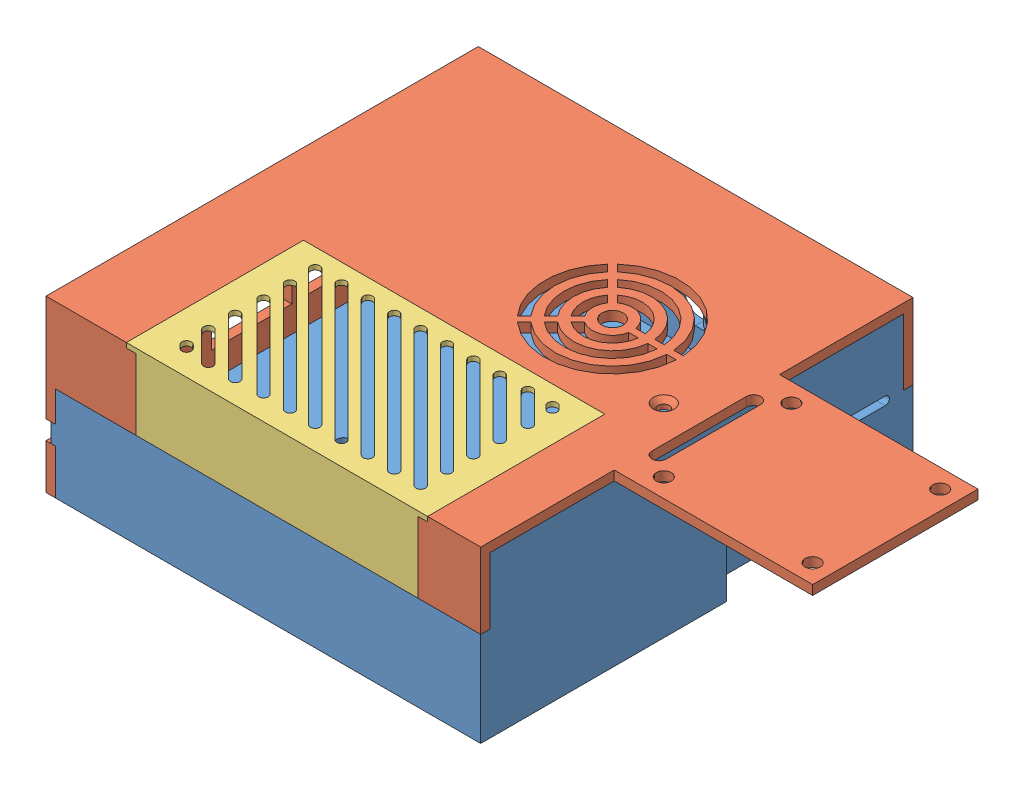
SolidWorks assembly ASSEMBLY_CASE, configuration Default. Lengths in mm.
Overall size (134.06 36 91.55).
3 component instances, 3 part files, 4 mates.
Components (placement in the parent):
- Raspberry Pi Case_BOTTOM_V2-1: Raspberry Pi Case_BOTTOM_V2 [Default] at (31.3282 21.7944 77.4978) size (91 34.05 91.55)
- Raspberry Pi Case_TOP_V2-1: Raspberry Pi Case_TOP_V2 [Default] at (31.3282 54.7944 77.4978) size (134.06 36 91.5)
- GPIO_cover-1: GPIO_cover [Default] at (33.7032 54.7944 103.9978) size (63.75 16 37.5)
Mates (geometry in assembly coordinates):
- Coincident1: coincident: line of Raspberry Pi Case_BOTTOM_V2-1 through (76.8282 52.7944 33.7478) axis (0 -1 0); line of Raspberry Pi Case_TOP_V2-1 through (76.8282 38.7944 33.7478) axis (0 1 0)
- Coincident2: coincident: line of Raspberry Pi Case_BOTTOM_V2-1 through (76.8282 52.7944 121.2478) axis (0 0 -1); line of Raspberry Pi Case_TOP_V2-1 through (76.8282 52.7944 59.9978) axis (0 0 -1)
- Coincident3: coincident: line of Raspberry Pi Case_TOP_V2-1 through (3.8282 53.7944 85.7478) axis (-1 0 0); line of GPIO_cover-1 through (65.5782 53.7944 85.7478) axis (-1 0 0)
- Coincident4: coincident: plane of Raspberry Pi Case_TOP_V2-1 through (1.8282 18.7944 123.2478) normal (1 0 0); plane of GPIO_cover-1 through (1.8282 53.7944 122.2478) normal (-1 0 0)
